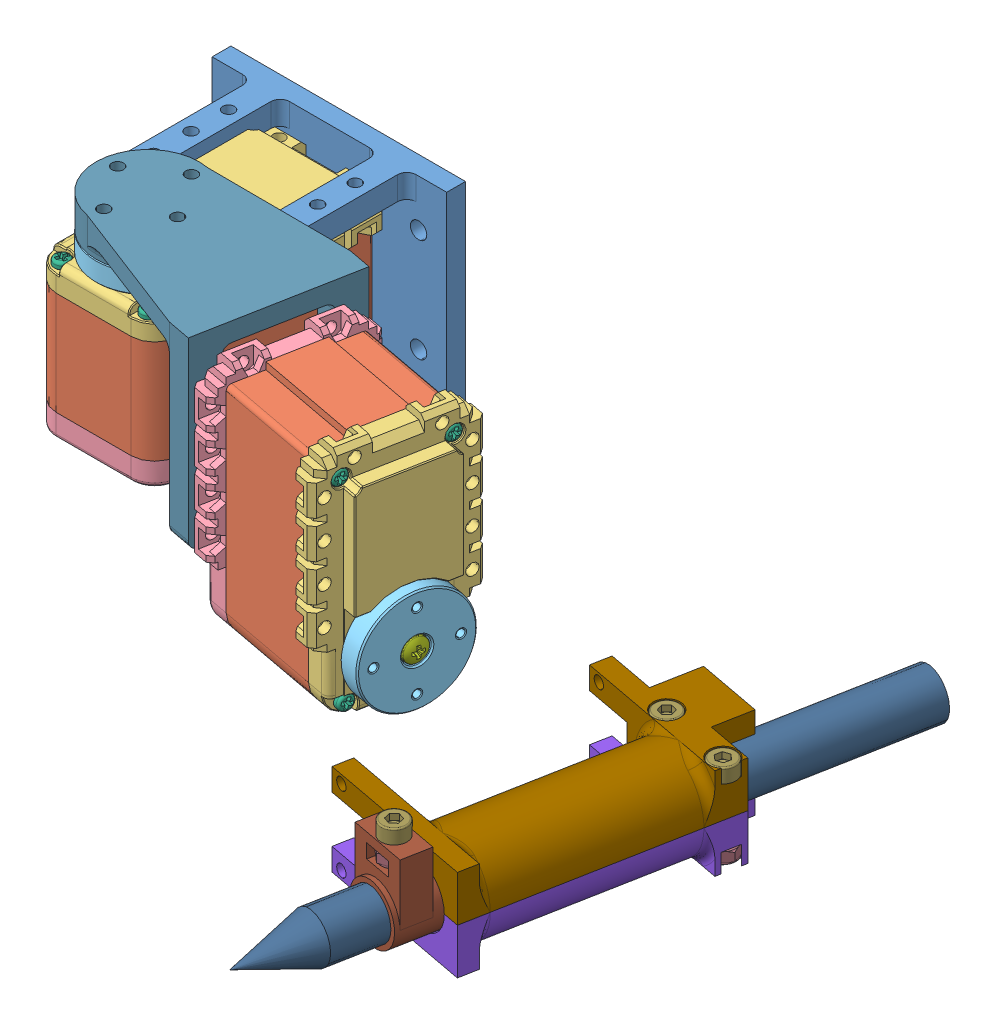
SolidWorks assembly ass_full, configuration Défaut. Lengths in mm.
Overall size (167.83 54.25 134.65).
35 component instances, 14 part files, 6 mates.
Components (placement in the parent):
- ass_support_couderV3-1: ass_support_couderV3 [Défaut] at (0.283 3.4024 -0.625) size (50 42.55 54.25)
  - support_couderV3-1: support_couderV3 [Défaut] at (-10.7404 1.2972 30.25) size (50 42 39.5)
  - AX-12A-1: AX-12A [Default] at (-10.7404 1.2972 73) x (0 0 -1) z (0 1 0) size (50 32 40.55)
    - AX-12A-01-1: AX-12A-01 [Default] at origin size (48.5 26 22)
    - AX-12A-02-1: AX-12A-02 [Default] at (0 0 13.5) size (50 32 8)
    - AX-12A-03-1: AX-12A-03 [Default] at (0 0 -13.5) x (1 0 0) z (0 0 -1) size (50 32 8)
    - AX-12A-04-1: AX-12A-04 [Default] at (0 0 21) size (22 22 6.7)
    - SetScrew-5: SetScrew [Default] at (33 10.4 14.5) x (0.31498 0.949098 0) z (0 0 -1) size (3.3 3.3 29.44)
    - SetScrew-6: SetScrew [Default] at (-9 9.25 14.5) x (0.31498 0.949098 0) z (0 0 -1) size (3.3 3.3 29.44)
    - SetScrew-7: SetScrew [Default] at (-9 -9.25 14.5) x (-0.958559 0.284893 0) z (0 0 -1) size (3.3 3.3 29.44)
    - SetScrew-8: SetScrew [Default] at (33 -10.4 14.5) x (0.31498 0.949098 0) z (0 0 -1) size (3.3 3.3 29.44)
    - pan head cross recess screw_iso-1: pan head cross recess screw_iso [ISO 7045 - M2.5 x 8 - Z --- 8C] at (0 0 21.6) x (0 0 -1) z (1 0 0) size (10.05 5 5)
- ass_support_stylo_ON-1: ass_support_stylo_ON [Défaut] at (118.5886 -77.4477 102.5772) x (0.98277 0 0.184834) z (0 1 0) size (35.22 128 25.75)
  - support_stylo_mot1_ON-1: support_stylo_mot1_ON [Défaut] at (-9.655 27.9226 55.8974) size (33.99 61 10.21)
  - support_stylo_mot2_ON-1: support_stylo_mot2_ON [Défaut] at (-9.655 27.9226 75.3974) x (-1 0 0) z (0 0 -1) size (33.5 61 9.75)
  - stylo-1: stylo [Défaut] at (-9.655 64.9227 65.6474) x (-0.739372 0 0.673298) z (0 -1 0) size (10 10 128)
  - support_stylo-1: support_stylo [Défaut] at (-9.655 -17.0773 65.6474) x (0 0 -1) z (0 1 0) size (19 15 52)
  - socket head cap screw 4762_din-1: socket head cap screw 4762_din [EN ISO 4762 M3 x 16 - 16N] at (-17.155 21.8297 75.3974) x (0 0 -1) z (-0.845418 0.534105 0) size (19 5.5 5.5)
  - socket head cap screw 4762_din-2: socket head cap screw 4762_din [EN ISO 4762 M3 x 16 - 16N] at (-2.155 21.8297 75.3974) x (0 0 -1) z (1 0 0) size (19 5.5 5.5)
  - hex nut style 1 gradeab_din-1: hex nut style 1 gradeab_din [Hexagon Nut ISO 4032 - M3 - W - N] at (-17.155 21.8297 59.8974) x (0.866025 0.5 0) z (0 0 1) size (5.5 6.35 2.4)
  - hex nut style 1 gradeab_din-2: hex nut style 1 gradeab_din [Hexagon Nut ISO 4032 - M3 - W - N] at (-2.155 21.8297 59.8974) x (0.866025 0.5 0) z (0 0 1) size (5.5 6.35 2.4)
  - socket head cap screw 4762_din-3: socket head cap screw 4762_din [EN ISO 4762 M3 x 10 - 10N] at (-9.655 -33.0773 81.6474) x (0 0 -1) z (0.923728 0.383049 0) size (13 5.5 5.5)
  - hex nut style 1 gradeab_din-3: hex nut style 1 gradeab_din [Hexagon Nut ISO 4032 - M3 - W - N] at (-9.655 -33.0773 76.6474) size (5.5 6.35 2.4)
- ass_support_couderV3B-1: ass_support_couderV3B [Défaut] at (-2.001 -27.5504 71.946) x (0.184834 0 -0.98277) z (0 1 0) size (33 83.55 54.25)
  - support_couderV3B-1: support_couderV3B [Défaut] at (-1.9847 8.2315 53.25) size (33 46 39.5)
  - AX-12A-1: AX-12A [Default] at (-1.9847 -42.7685 17.5) x (0 0 1) z (0 -1 0) size (50 32 40.55)
    - AX-12A-01-1: AX-12A-01 [Default] at origin size (48.5 26 22)
    - AX-12A-02-1: AX-12A-02 [Default] at (0 0 13.5) size (50 32 8)
    - AX-12A-03-1: AX-12A-03 [Default] at (0 0 -13.5) x (1 0 0) z (0 0 -1) size (50 32 8)
    - AX-12A-04-1: AX-12A-04 [Default] at (0 0 21) size (22 22 6.7)
    - SetScrew-5: SetScrew [Default] at (33 10.4 14.5) x (0.31498 0.949098 0) z (0 0 -1) size (3.3 3.3 29.44)
    - SetScrew-6: SetScrew [Default] at (-9 9.25 14.5) x (0.31498 0.949098 0) z (0 0 -1) size (3.3 3.3 29.44)
    - SetScrew-7: SetScrew [Default] at (-9 -9.25 14.5) x (-0.958559 0.284893 0) z (0 0 -1) size (3.3 3.3 29.44)
    - SetScrew-8: SetScrew [Default] at (33 -10.4 14.5) x (0.31498 0.949098 0) z (0 0 -1) size (3.3 3.3 29.44)
    - pan head cross recess screw_iso-1: pan head cross recess screw_iso [ISO 7045 - M2.5 x 8 - Z --- 8C] at (0 0 21.6) x (0 0 -1) z (1 0 0) size (10.05 5 5)
Mates (geometry in assembly coordinates):
- Coaxiale1: concentric aligned: cylinder of ass_support_couderV3-1/AX-12A-1/AX-12A-04-1 through (-10.4575 25.6996 72.375) axis (0 -1 0) radius 11; cylinder of ass_support_couderV3B-1/support_couderV3B-1 through (-10.4575 32.6996 72.375) axis (0 -1 0) radius 11
- Coïncidente1: coincident anti-aligned: plane of ass_support_couderV3-1/AX-12A-1/AX-12A-04-1 through (-13.2075 25.6996 72.375) normal (0 1 0); plane of ass_support_couderV3B-1/support_couderV3B-1 through (-10.4575 25.6996 72.375) normal (0 -1 0)
- Coïncidente2: coincident anti-aligned: plane of ass_support_stylo_ON-1/support_stylo_mot1_ON-1 through (122.1624 -16.5504 84.0895) normal (-0.184834 0 0.98277); plane of ass_support_couderV3B-1/AX-12A-1/AX-12A-01-1 through (52.8771 25.4496 71.0587) normal (0.184834 0 -0.98277)
- Parallèle1: parallel aligned: plane of ass_support_stylo_ON-1/support_stylo_mot2_ON-1 through (114.2611 -2.0504 73.3512) normal (0 1 0); plane of ass_support_couderV3B-1/AX-12A-1/AX-12A-01-1 through (49.4115 26.9496 89.4856) normal (0 1 0)
- Distance1: distance = 32 mm anti-aligned: plane of ass_support_stylo_ON-1/support_stylo_mot2_ON-1 through (90.9203 -2.0504 68.9614) normal (-0.98277 0 -0.184834); plane of ass_support_couderV3B-1/AX-12A-1/AX-12A-02-1 through (55.3881 -10.0504 84.7589) normal (0.98277 0 0.184834)
- Coïncidente5: coincident aligned: plane of ass_support_stylo_ON-1/support_stylo_mot1_ON-1 through (114.2611 -21.5504 73.3512) normal (0 -1 0); plane of ass_support_couderV3B-1/AX-12A-1/AX-12A-01-1 through (52.8771 -21.5504 71.0587) normal (0 -1 0)
